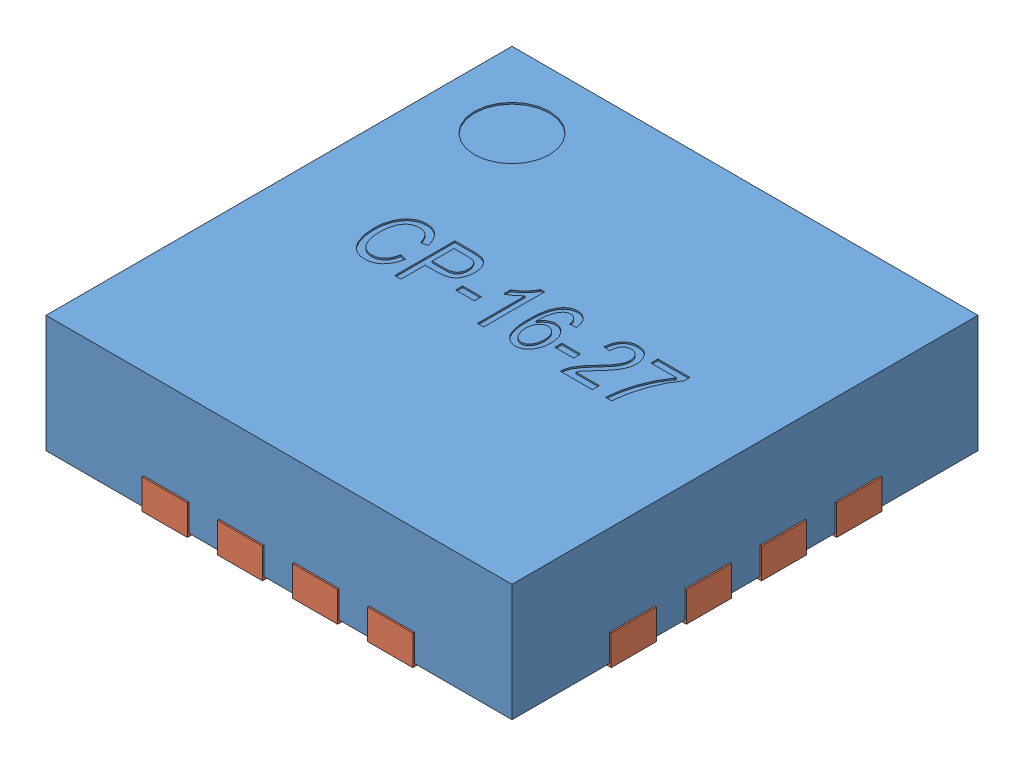
SolidWorks assembly Assem1, configuration Default. Lengths in mm.
Overall size (3.12 0.8 3.12).
18 component instances, 3 part files, 12 mates.
Components (placement in the parent):
- Body-1: Body [Default] at (0 0.02 0) size (3.1 0.78 3.1)
- P-1: P [Default] at (-1.38 0 -0.75) x (0 0 1) z (-1 0 0) size (0.3 0.2 0.51)
- P-2: P [Default] at (-1.38 0 -0.25) x (0 0 1) z (-1 0 0) size (0.3 0.2 0.51)
- P-3: P [Default] at (-1.38 0 0.25) x (0 0 1) z (-1 0 0) size (0.3 0.2 0.51)
- P-4: P [Default] at (-1.38 0 0.75) x (0 0 1) z (-1 0 0) size (0.3 0.2 0.51)
- P-5: P [Default] at (1.38 0 -0.75) x (0 0 -1) z (1 0 0) size (0.3 0.2 0.51)
- P-6: P [Default] at (1.38 0 -0.25) x (0 0 -1) z (1 0 0) size (0.3 0.2 0.51)
- P-7: P [Default] at (1.38 0 0.25) x (0 0 -1) z (1 0 0) size (0.3 0.2 0.51)
- P-8: P [Default] at (1.38 0 0.75) x (0 0 -1) z (1 0 0) size (0.3 0.2 0.51)
- P-9: P [Default] at (-0.75 0 1.38) size (0.3 0.2 0.51)
- P-10: P [Default] at (-0.25 0 1.38) size (0.3 0.2 0.51)
- P-11: P [Default] at (0.25 0 1.38) size (0.3 0.2 0.51)
- P-12: P [Default] at (0.75 0 1.38) size (0.3 0.2 0.51)
- P-13: P [Default] at (-0.75 0 -1.38) x (-1 0 0) z (0 0 -1) size (0.3 0.2 0.51)
- P-14: P [Default] at (-0.25 0 -1.38) x (-1 0 0) z (0 0 -1) size (0.3 0.2 0.51)
- P-15: P [Default] at (0.25 0 -1.38) x (-1 0 0) z (0 0 -1) size (0.3 0.2 0.51)
- P-16: P [Default] at (0.75 0 -1.38) x (-1 0 0) z (0 0 -1) size (0.3 0.2 0.51)
- EP-1: EP [Default] at (0 0.2 0) x (-1 0 0) z (0 0 1) size (1.65 0.2 1.65)
Mates (geometry in assembly coordinates):
- Coincident1: coincident: plane of Body-1 through (0 0.02 0) normal (0 0 1); plane of assembly through (0 0 0) normal (0 0 1)
- Coincident2: coincident: plane of Body-1 through (0 0.02 0) normal (1 0 0); plane of assembly through (0 0 0) normal (1 0 0)
- Distance1: distance = 0.02 mm: plane of Body-1 through (0 0.02 0) normal (0 -1 0); plane of assembly through (0 0 0) normal (0 1 0)
- Coincident4: coincident: plane of P-1 through (-1.2 0 -0.75) normal (0 -1 0); plane of assembly through (0 0 0) normal (0 1 0)
- Distance2: distance = 0.01 mm: plane of P-1 through (-1.56 0.2 -0.9) normal (-1 0 0); plane of Body-1 through (-1.55 0.8 1.55) normal (-1 0 0)
- Distance3: distance = 0.75 mm: plane of P-1 through (-1.38 0 -0.75) normal (0 0 1); plane of assembly through (0 0 0) normal (0 0 1)
- Coincident7: coincident: plane of P-9 through (-0.75 0 1.2) normal (0 -1 0); plane of assembly through (0 0 0) normal (0 1 0)
- Distance4: distance = 0.01 mm: plane of P-9 through (-0.9 0.2 1.56) normal (0 0 1); plane of Body-1 through (-1.55 0.8 1.55) normal (0 0 1)
- Distance5: distance = 0.75 mm: plane of P-9 through (-0.75 0 1.38) normal (1 0 0); plane of assembly through (0 0 0) normal (1 0 0)
- Coincident10: coincident: plane of EP-1 through (0 0.2 0) normal (0 0 1); plane of assembly
- Coincident11: coincident: plane of EP-1 through (0 0.2 0) normal (-1 0 0); plane of assembly
- Coincident12: coincident: plane of P-4 through (-1.2 0 0.75) normal (0 -1 0); plane of EP-1 through (0 0 0) normal (0 -1 0)
